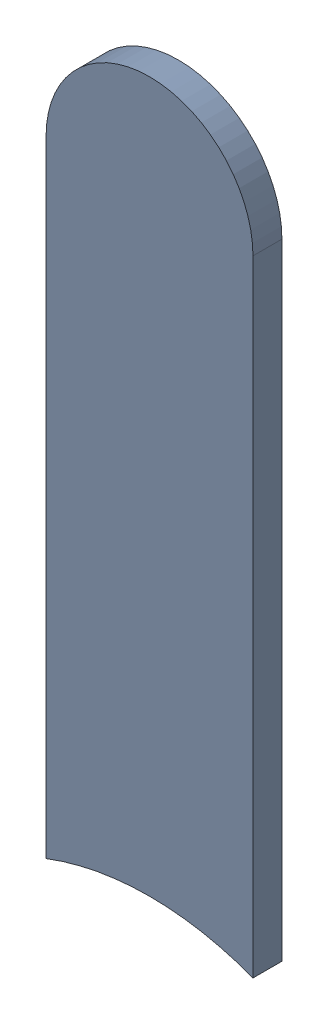
SolidWorks assembly Track (24.4mm,48.5mm)(24.4mm,49.6mm) on Bottom Layer, configuration Predeterminado. Lengths in mm.
Overall size (0.25 0.89 0.04).
2 component instances, 1 part files, 0 mates.
Components (placement in the parent):
- Track (24.4mm,48.5mm)(24.4mm,49.6mm) on Bottom Layer-1-1: Track (24.4mm,48.5mm)(24.4mm,49.6mm) on Bottom Layer-1 [Predeterminado] at (-68.317 -44.187 -0.4013) size (0.25 0.89 0.04)
  - Track (24.4mm,48.5mm)(24.4mm,49.6mm) on Bottom Layer-Part-1-1: Track (24.4mm,48.5mm)(24.4mm,49.6mm) on Bottom Layer-Part-1 [Predeterminado] at origin size (0.25 0.89 0.04)
